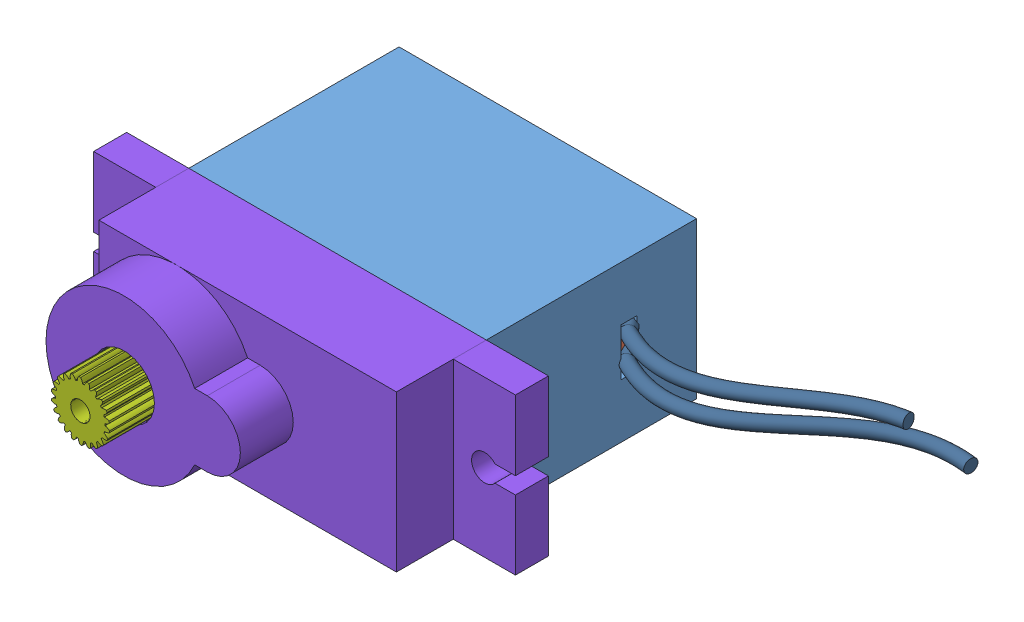
SolidWorks assembly servo-motor-montaj, configuration Varsayılan. Lengths in mm.
Overall size (45.89 13.05 32.84).
11 component instances, 10 part files, 0 mates.
Components (placement in the parent):
- SERVO_MOTEUR-1: SERVO_MOTEUR [Default] at origin size (45.89 13.05 32.84)
  - lower cover-1: lower cover [Varsayılan] at (-10.9275 3.0017 -4.223) size (22.5 11.8 15.9)
  - motor-1: motor [Varsayılan] at (-9.5275 2.9783 11.077) x (-0.99999 -0.004374 0) z (0 0 -1) size (7.83 7.83 13.56)
  - feedback potentiometer-1: feedback potentiometer [Varsayılan] at (-9.0275 3.0017 11.177) x (-1 0 0) z (0 0 -1) size (7.71 7.36 13.7)
  - Part6^servo motor assembley-1: Part6^servo motor assembley [Varsayılan] at (-10.9275 3.0017 11.177) x (-1 0 0) z (0 0 -1) size (1.5 1.5 10)
  - Part7^servo motor assembley-1: Part7^servo motor assembley [Varsayılan] at (-9.517 2.6091 11.927) x (0.924877 -0.380266 0) z (0 0 1) size (10 10 5.7)
  - Part8^servo motor assembley-1: Part8^servo motor assembley [Varsayılan] at (-9.3501 4.3681 11.477) x (0.966834 -0.255406 0) z (0 0 1) size (3.22 3.24 1.95)
  - Part10^servo motor assembley-1: Part10^servo motor assembley [Varsayılan] at (-11.9047 8.7845 13.077) x (0.603146 0.797631 0) z (0 0 1) size (8.02 8.02 12.7)
  - upper cover-1: upper cover [Varsayılan] at (-10.9275 3.0017 11.677) x (-1 0 0) z (0 0 1) size (31.9 11.8 10.8)
  - Part16^servo motor assembley-1: Part16^servo motor assembley [Varsayılan] at (-10.9275 3.0017 -3.723) size (11.69 9.5 1.25)
  - Part21^servo motor assembley-1: Part21^servo motor assembley [Varsayılan] at (-10.9275 -2.8983 -4.223) x (-1 0 0) z (0 -1 0) size (34.03 15.81 10.46)
